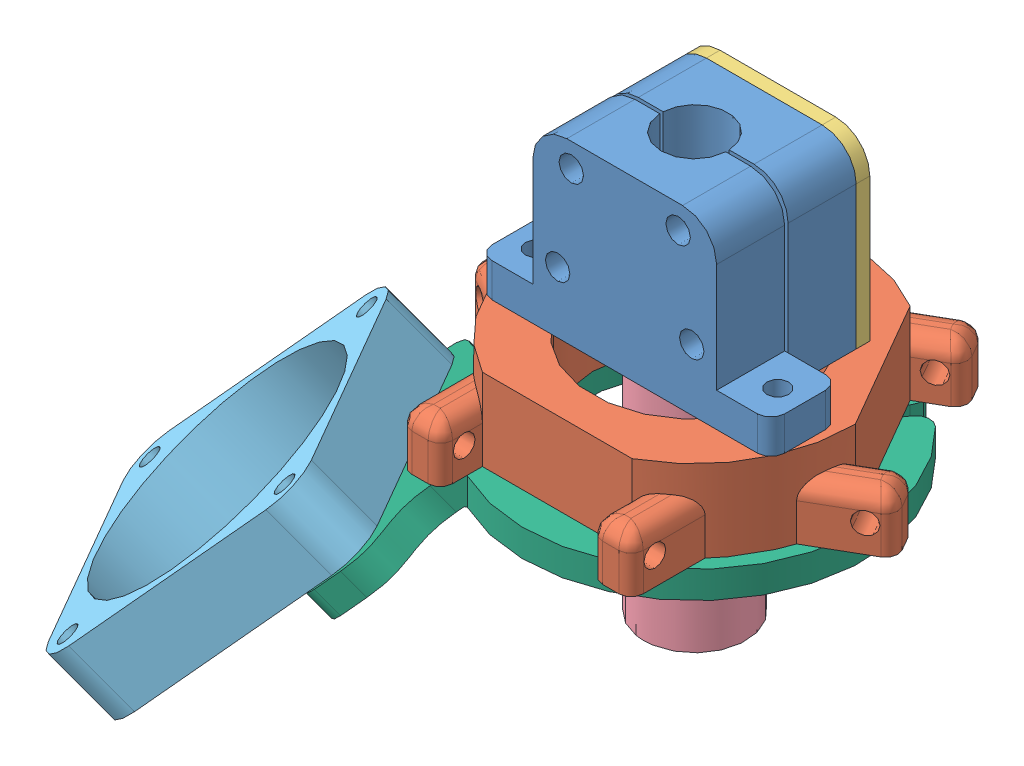
SolidWorks assembly Effector And Hot End, configuration Default. Lengths in mm.
Overall size (100.87 73.71 84.22).
7 component instances, 6 part files, 16 mates.
Components (placement in the parent):
- Hot End Holder-3: Hot End Holder [Default] at origin size (27 26 10)
- Hot End Holder-4: Hot End Holder [With Wings] at (0 0 0.5) x (-1 0 0) z (0 0 -1) size (43 26 10)
- Platform-1: Platform [Default] at (0 -12 0.2) x (1 0 0) z (0 1 0) size (61.36 53.62 12)
- Hot End Plate-1: Hot End Plate [Default] at (0 0 -10) x (-1 0 0) z (0 0 -1) size (27 26 12)
- Hot End-1: Hot End [Default] at (0 -35 0.2) size (15 50 15)
- Fan-1: Fan [Default] at (-38.3468 -33.5668 22.3395) x (0.612372 0.707107 -0.353553) z (0.5 0 0.866025) size (40 10 40)
- Fan and LED Mount-1: Fan and LED Mount [Default] at (0 -12 0.2) x (0.5 0 0.866025) z (0 -1 0) size (50 61.85 16.97)
Mates (geometry in assembly coordinates):
- Distance1: distance = 0.5 mm anti-aligned: plane of Hot End Holder-4 through (13.5 15 0.5) normal (0 0 -1); plane of Hot End Holder-3 through (-13.5 15 0) normal (0 0 1)
- Coincident2: coincident aligned: plane of Hot End Holder-3 through (13.5 15 -10) normal (1 0 0); plane of Hot End Holder-4 through (13.5 15 10.5) normal (1 0 0)
- Coincident3: coincident aligned: plane of Hot End Holder-3 through (0 26 0.2) normal (0 1 0); plane of Hot End Holder-4 through (0 26 0.3) normal (0 1 0)
- Coincident4: coincident anti-aligned: plane of Hot End Holder-3 through (-13.5 0 0) normal (0 -1 0); plane of Platform-1 through (0 0 0.2) normal (0 1 0)
- Concentric1: concentric anti-aligned: cylinder of Hot End Holder-3 through (0 0 0.2) axis (0 1 0) radius 8; cylinder of Platform-1 through (0 0 0.2) axis (0 -1 0) radius 15
- Coincident5: coincident anti-aligned: plane of Hot End Holder-3 through (-13.5 15 -10) normal (0 0 -1); plane of Hot End Plate-1 through (13.5 0 -10) normal (0 0 1)
- Coincident6: coincident anti-aligned: plane of Hot End Holder-3 through (0 0 0) normal (1 0 0); plane of Hot End Plate-1 through (0 0 -10) normal (-1 0 0)
- Coincident7: coincident aligned: plane of Hot End Holder-3 through (0 0 0) normal (0 1 0); plane of Hot End Plate-1
- Coincident9: coincident anti-aligned: plane of Hot End Holder-3 through (0 15 0.2) normal (0 -1 0); plane of Hot End-1 through (0 15 0.2) normal (0 1 0)
- Concentric3: concentric anti-aligned: cylinder of Hot End Holder-3 through (0 0 0.2) axis (0 1 0) radius 8; cylinder of Hot End-1 through (0 15 0.2) axis (0 -1 0) radius 7.5
- Coincident11: coincident anti-aligned: plane of Platform-1 through (0 -12 0.2) normal (0 -1 0); plane of Fan and LED Mount-1 through (0 -12 0.2) normal (0 1 0)
- Angle1: planar angle = 1.047198 rad aligned: plane of Fan and LED Mount-1; plane of assembly through (0 0 0) normal (0 0 1)
- Coincident14: coincident anti-aligned: plane of Fan-1 through (-36.0994 -19.4246 -2.052) normal (0.612372 -0.707107 -0.353553); plane of Fan and LED Mount-1 through (-16.2534 -18.0148 29.5025) normal (-0.612372 0.707107 0.353553)
- Concentric9: concentric aligned: cylinder of Fan-1 through (-36.4927 -21.8995 2.2165) axis (-0.612372 0.707107 0.353553) radius 1.5; cylinder of Fan and LED Mount-1 through (-8.4833 -54.2419 -13.9547) axis (-0.612372 0.707107 0.353553) radius 2
- Concentric10: concentric aligned: cylinder of Fan-1 through (-19.9927 -21.8995 30.7953) axis (-0.612372 0.707107 0.353553) radius 1.5; cylinder of Fan and LED Mount-1 through (8.0167 -54.2419 14.6241) axis (-0.612372 0.707107 0.353553) radius 2
- Concentric11: concentric anti-aligned: cylinder of Platform-1 through (0 0 0.2) axis (0 -1 0) radius 15; cylinder of Fan and LED Mount-1 through (0 -16 0.2) axis (0 1 0) radius 16
